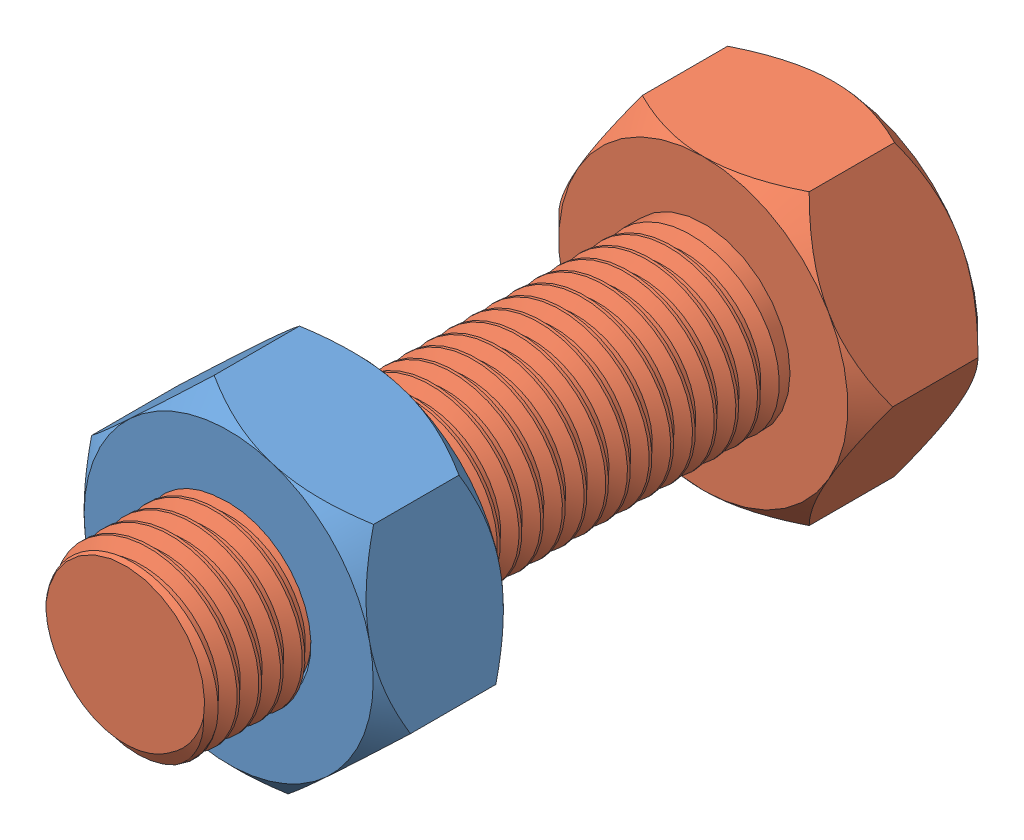
SolidWorks assembly Assem1, configuration Default. Lengths in mm.
Overall size (30.18 26.62 49.73).
2 component instances, 2 part files, 6 mates.
Components (placement in the parent):
- Nut-1: Nut [Default] at (0 0 32.8348) x (0.955141 -0.29615 0) z (0 0 1) size (25.4 20 10.05)
- Bolt-1: Bolt [Default] x (-1 0 0) z (0 0 1) size (25.4 20 49.73)
Mates (geometry in assembly coordinates):
- Coincident2: coincident anti-aligned: line of Nut-1 through (0 0 33.6677) axis (0 0 1); line of Bolt-1 through (0 0 44) axis (0 0 -1)
- Screw1: screw = 1.5 mm anti-aligned: cylinder of Nut-1 through (0 0 33.6677) axis (0 0 1); cylinder of Bolt-1 through (0 0 44.5) axis (0 0 -1) radius 6
- Coincident3: coincident anti-aligned: plane of Bolt-1 through (0 0 0) normal (0 -1 0)
- Coincident4: coincident aligned: plane of Bolt-1 through (0 0 0) normal (0 0 1)
- Coincident6: coincident anti-aligned: plane of Bolt-1 through (0 0 0) normal (-1 0 0)
- LimitDistance1: limit distance = 23.8348 mm anti-aligned: plane of Nut-1 through (0 0 28.3348) normal (0 0 -1); plane of Bolt-1 through (0 0 4.5) normal (0 0 1)
